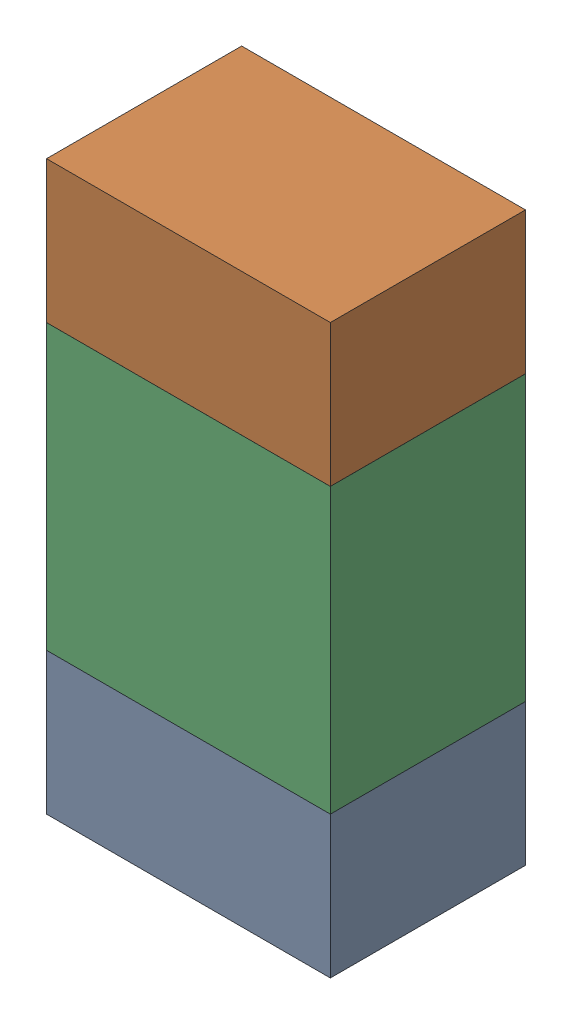
SolidWorks assembly R52, configuration ﾃﾞﾌｫﾙﾄ. Lengths in mm.
Overall size (0.8 1.6 0.55).
6 component instances, 2 part files, 0 mates.
Components (placement in the parent):
- 689261784-1: 689261784 [ﾃﾞﾌｫﾙﾄ] at (40.3226 21.9426 -1.7503) size (0.8 0.4 0.55)
  - Extruded_34-1: Extruded_34 [ﾃﾞﾌｫﾙﾄ] at origin size (0.8 0.4 0.55)
- 689261784-2: 689261784 [ﾃﾞﾌｫﾙﾄ] at (40.3226 23.1426 -1.7503) size (0.8 0.4 0.55)
  - Extruded_34-1: Extruded_34 [ﾃﾞﾌｫﾙﾄ] at origin size (0.8 0.4 0.55)
- 689261648-1: 689261648 [ﾃﾞﾌｫﾙﾄ] at (40.3226 22.5425 -1.7503) size (0.8 0.8 0.55)
  - Extruded_33-1: Extruded_33 [ﾃﾞﾌｫﾙﾄ] at origin size (0.8 0.8 0.55)
